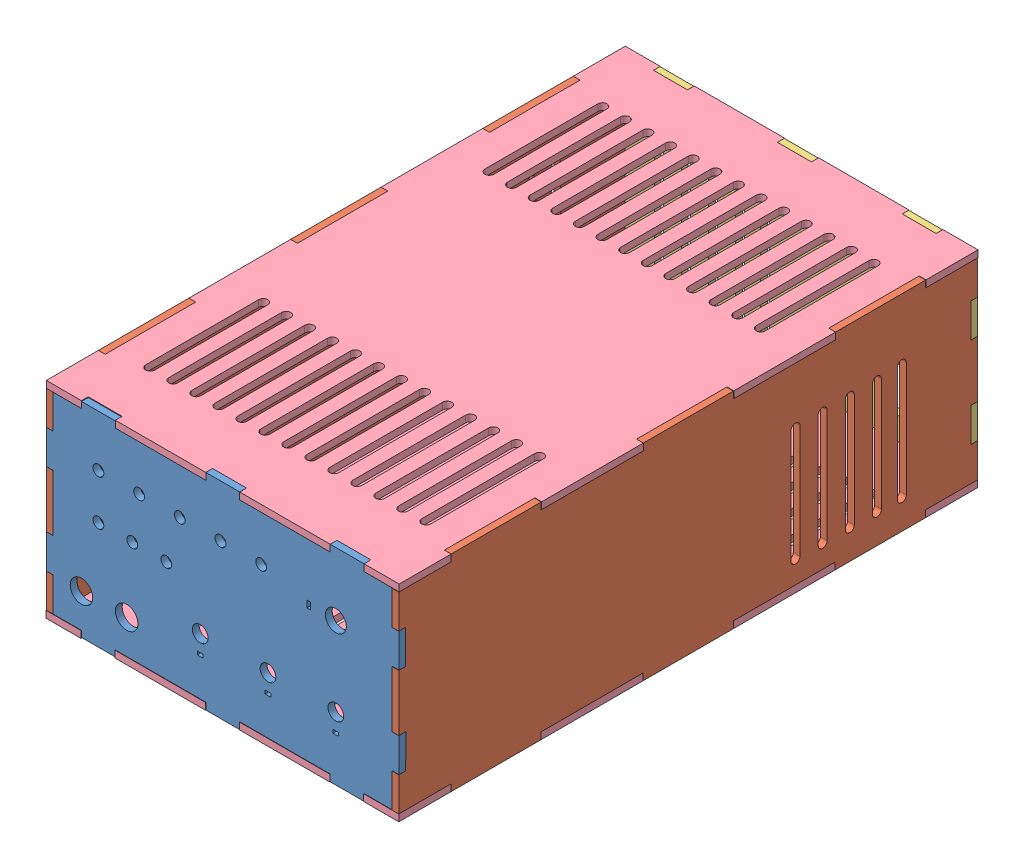
SolidWorks assembly functionGen, configuration Default. Lengths in mm.
Overall size (156 91.04 256.2).
6 component instances, 4 part files, 15 mates.
Components (placement in the parent):
- front_plate-1: front_plate [Default] at (23.3505 101.6123 127.1304) size (156 91.04 3)
- side_plate1-1: side_plate1 [Default] at (110.7652 98.3596 -95.1445) x (0 0 -1) z (1 0 0) size (256 91 3)
- side_plate1-2: side_plate1 [Default] at (-42.2348 98.3596 -95.3065) x (0 0 -1) z (1 0 0) size (256 91 3)
- back_plate-2: back_plate [Default] at (25.7374 98.3596 -125.7075) size (156 91.02 3)
- bottom_plate-2: bottom_plate [Default] at (25.7374 128.2774 -92.8426) x (1 0 0) z (0 1 0) size (156 256.04 3)
- bottom_plate-3: bottom_plate [Default] at (25.7374 40.2774 -92.6806) x (1 0 0) z (0 1 0) size (156 256.04 3)
Mates (geometry in assembly coordinates):
- Coincident1: coincident anti-aligned: plane of front_plate-1 through (113.7652 113.2774 130.1304) normal (0 1 0); plane of side_plate1-1 through (113.7652 113.2774 130.2925) normal (0 -1 0)
- Coincident2: coincident anti-aligned: plane of front_plate-1 through (110.7652 73.2774 130.1304) normal (0 1 0); plane of side_plate1-1 through (113.7652 73.2774 130.2925) normal (0 -1 0)
- Coincident7: coincident anti-aligned: plane of front_plate-1 through (110.7652 98.2774 130.1304) normal (1 0 0); plane of side_plate1-1 through (110.7652 98.3596 -95.1445) normal (-1 0 0)
- Coincident8: coincident anti-aligned: plane of front_plate-1 through (-42.2348 113.2774 130.1304) normal (0 1 0); plane of side_plate1-2 through (-39.2348 113.2774 130.1304) normal (0 -1 0)
- Coincident9: coincident anti-aligned: plane of front_plate-1 through (-39.2348 98.2774 130.1304) normal (-1 0 0); plane of side_plate1-2 through (-39.2348 98.3596 -95.3065) normal (1 0 0)
- Coincident10: coincident anti-aligned: plane of front_plate-1 through (23.3505 101.6123 127.1304) normal (0 0 -1); plane of side_plate1-2 through (-39.2348 73.2774 127.1304) normal (0 0 1)
- Coincident11: coincident anti-aligned: plane of side_plate1-1 through (113.7652 113.2774 -125.7075) normal (0 -1 0); plane of back_plate-2 through (113.7652 113.2774 -122.7075) normal (0 1 0)
- Coincident12: coincident anti-aligned: plane of side_plate1-1 through (113.7652 113.2774 -122.7075) normal (0 0 -1); plane of back_plate-2 through (25.7374 98.3596 -122.7075) normal (0 0 1)
- Coincident13: coincident anti-aligned: plane of side_plate1-1 through (110.7652 98.3596 -95.1445) normal (-1 0 0); plane of back_plate-2 through (110.7652 98.2774 -122.7075) normal (1 0 0)
- Coincident14: coincident anti-aligned: plane of front_plate-1 through (98.2652 131.2774 130.1304) normal (1 0 0); plane of top_plate-2 through (98.2652 131.2774 130.1304) normal (-1 0 0)
- Coincident15: coincident anti-aligned: plane of front_plate-1 through (23.3505 101.6123 127.1304) normal (0 0 -1); plane of top_plate-2 through (83.2652 131.2774 127.1304) normal (0 0 1)
- Coincident20: coincident anti-aligned: plane of side_plate1-1 through (113.7652 128.2774 130.2925) normal (0 1 0); plane of top_plate-2 through (25.7374 128.2774 -92.8426) normal (0 -1 0)
- Coincident21: coincident anti-aligned: plane of back_plate-2 through (98.2652 40.2774 -122.7075) normal (1 0 0); plane of bottom_plate-3 through (98.2652 43.2774 -125.7075) normal (-1 0 0)
- Coincident22: coincident anti-aligned: plane of back_plate-2 through (98.2652 43.2774 -122.7075) normal (0 -1 0); plane of bottom_plate-3 through (25.7374 43.2774 -92.6806) normal (0 1 0)
- Coincident23: coincident anti-aligned: plane of back_plate-2 through (25.7374 98.3596 -122.7075) normal (0 0 1); plane of bottom_plate-3 through (83.2652 43.2774 -122.7075) normal (0 0 -1)
